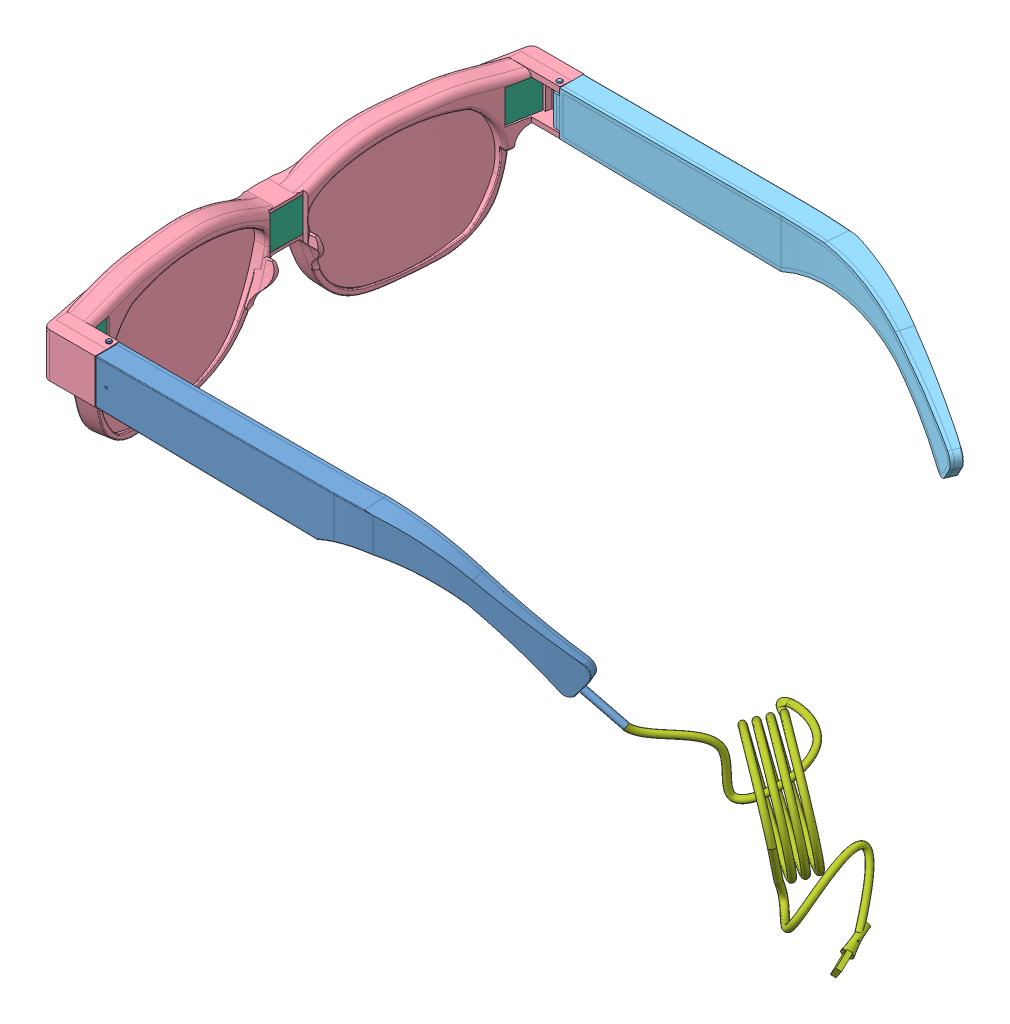
SolidWorks assembly Gafas WC 2023, configuration Default. Lengths in mm.
Overall size (222.66 106.19 146.27).
10 component instances, 7 part files, 27 mates.
Components (placement in the parent):
- Part1-1: Part1 [Default] at (-33.5143 33.5628 22.7781) size (139.98 37.93 22.05)
- Speaker chamber-1: Speaker chamber [Default] at (-37.5533 32.8602 20.2781) x (1 0 0) z (0 -1 0) size (14 4 6)
- PCB-4: PCB [Default] at (-77.7829 13.9335 20.2781) x (-1 0 0) z (0 1 0) size (45 3 10)
- frame-1: frame [Default] at (-140.5612 55.2655 184.5273) x (0 0 1) z (-1 0 0) size (143.47 53.42 27.49)
- Right Arm-1: Right Arm [Default] at (-38.6057 4.972 -63.5743) size (132.64 32.79 22.04)
- cmm-3: cmm [Default] at (-112.6806 14.0335 -108.5367) x (-0.178629 0 0.983916) z (-0.983916 0 -0.178629) size (10 10 7)
- cmm-4: cmm [Default] at (-119.3105 10.3315 -45.3241) x (0 1 0) z (-0.999885 0 -0.015171) size (10 10 7)
- cmm-6: cmm [Default] at (-112.6806 14.0335 17.7973) x (0 1 0) z (-0.983916 0 0.178629) size (10 10 7)
- Speaker chamber-3: Speaker chamber [Default] at (-38.8332 33.3633 -115.0175) x (1 0 0) z (0 -1 0) size (14 4 6)
- wire-1: wire [Default] at (9.152 -55.6539 -61.161) x (0.629187 0.526286 0.571967) z (0.535942 -0.826727 0.171142) size (40.55 44.6 63.29)
Mates (geometry in assembly coordinates):
- Coincident4: coincident anti-aligned: plane of Part1-1 through (-33.5143 33.5628 20.2781) normal (0 0 1); plane of Speaker chamber-1 through (-37.5533 32.8602 20.2781) normal (0 0 -1)
- Coincident5: coincident anti-aligned: line of Part1-1 through (-52.2245 9.2086 20.2781) axis (0 1 0); line of Speaker chamber-1 through (-52.2245 13.2086 20.2781) axis (0 -1 0)
- Coincident6: coincident: line of Part1-1 through (-48.1799 15.2086 20.2781) axis (1 0 0); plane of Speaker chamber-1 through (-38.2245 15.2086 24.2781) normal (0 1 0)
- Coincident13: coincident anti-aligned: plane of Part1-1 through (-33.5143 33.5628 20.2781) normal (0 0 1); plane of PCB-4 through (-77.7829 13.9335 20.2781) normal (0 0 -1)
- Coincident14: coincident: line of Part1-1 through (-100.2829 8.9335 20.2781) axis (0 1 0); plane of PCB-4 through (-100.2829 8.9335 21.2781) normal (-1 0 0)
- Coincident15: coincident: line of Part1-1 through (-100.2829 18.9335 20.2781) axis (1 0 0); plane of PCB-4 through (-100.2829 18.9335 21.2781) normal (0 1 0)
- Concentric1: concentric anti-aligned: cylinder of Part1-1 through (-105.0143 21.0335 20.7781) axis (0 -1 0) radius 0.75; cylinder of frame-1 through (-105.0143 -10.9665 20.7781) axis (0 1 0) radius 0.75
- Concentric2: concentric anti-aligned: cylinder of Part1-1 through (-105.0143 21.0335 20.7781) axis (0 -1 0) radius 0.75; cylinder of frame-1 through (-105.0143 -10.9665 20.7781) axis (0 1 0) radius 0.75
- Concentric3: concentric anti-aligned: cylinder of Part1-1 through (-105.0143 21.0335 20.7781) axis (0 -1 0) radius 0.75; cylinder of frame-1 through (-105.0143 -10.9665 20.7781) axis (0 1 0) radius 0.75
- Distance2: distance = 0.5 mm anti-aligned: plane of Part1-1 through (-103.5143 18.5335 22.2781) normal (0 1 0); plane of frame-1 through (207.2617 19.0335 -45.3697) normal (0 -1 0)
- LimitAngle1: limit planar angle = 0 rad anti-aligned: plane of Part1-1 through (-103.5143 33.5628 22.7781) normal (-1 0 0); plane of frame-1 through (-103.5143 22.0177 -25.1351) normal (1 0 0)
- Distance3: distance = 0.5 mm anti-aligned: plane of Right Arm-1 through (-106.5143 18.5335 -110.0175) normal (0 1 0); plane of frame-1 through (207.2617 19.0335 -45.3697) normal (0 -1 0)
- LimitAngle2: limit planar angle = 0 rad anti-aligned: plane of frame-1 through (-103.5143 22.0177 -65.6043) normal (1 0 0); plane of Right Arm-1 through (-103.5143 4.972 -113.5175) normal (-1 0 0)
- Tangent3: tangent: plane of assembly; face of frame-1; plane of cmm-3 through (-119.568 14.0335 -109.7871) normal (-0.983916 0 -0.178629)
- Coincident16: coincident anti-aligned: plane of frame-1 through (-117.0175 14.0335 -104.2423) normal (0.178629 0 -0.983916); plane of cmm-3 through (-120.4612 19.0335 -104.8675) normal (-0.178629 0 0.983916)
- Coincident17: coincident anti-aligned: plane of frame-1 through (207.2617 9.0335 -45.3697) normal (0 1 0); plane of cmm-3 through (-120.4612 9.0335 -104.8675) normal (0 -1 0)
- Coincident20: coincident anti-aligned: plane of frame-1 through (207.2617 5.3315 -45.3697) normal (0 1 0); plane of cmm-4 through (-126.2339 5.3315 -50.4297) normal (0 -1 0)
- Distance4: distance = 0 mm anti-aligned: plane of cmm-4 through (-126.2339 15.3315 -50.4297) normal (0.015171 0 -0.999885); plane of frame-1 through (-122.2804 10.3315 -50.3697) normal (-0.015171 0 0.999885)
- Tangent4: tangent: plane of assembly; face of frame-1; plane of cmm-6 through (-119.568 14.0335 19.0477) normal (-0.983916 0 0.178629)
- Coincident26: coincident anti-aligned: plane of frame-1 through (207.2617 19.0335 -45.3697) normal (0 -1 0); plane of cmm-6 through (-120.4612 19.0335 14.1281) normal (0 1 0)
- Coincident27: coincident anti-aligned: plane of frame-1 through (-117.0175 14.0335 13.5029) normal (0.178629 0 0.983916); plane of cmm-6 through (-120.4612 19.0335 14.1281) normal (-0.178629 0 -0.983916)
- Concentric4: concentric aligned: cylinder of frame-1 through (-105.0143 29.0335 -111.5175) axis (0 -1 0) radius 0.75; cylinder of Right Arm-1 through (-105.0143 21.0335 -111.5175) axis (0 -1 0) radius 0.75
- Coincident31: coincident anti-aligned: plane of Right Arm-1 through (-108.6057 24.972 -111.0175) normal (0 0 -1); plane of Speaker chamber-3 through (-38.8332 33.3633 -111.0175) normal (0 0 1)
- Coincident32: coincident: line of Right Arm-1 through (-49.4598 15.7117 -111.0175) axis (1 0 0); plane of Speaker chamber-3 through (-39.5044 15.7117 -111.0175) normal (0 1 0)
- Coincident33: coincident: line of Right Arm-1 through (-39.5044 15.7117 -111.0175) axis (0 -1 0); plane of Speaker chamber-3 through (-39.5044 11.7117 -111.0175) normal (1 0 0)
- Coincident34: coincident anti-aligned: plane of Part1-1 through (32.9187 -15.123 6.8635) normal (0.77579 -0.55894 -0.292809); plane of wire-1 through (33.0846 -14.9931 7.0552) normal (-0.77579 0.55894 0.292809)
- Coincident35: coincident anti-aligned: plane of Part1-1 through (32.9187 -15.123 6.8635) normal (0.77579 -0.55894 -0.292809); plane of wire-1 through (33.0846 -14.9931 7.0552) normal (-0.77579 0.55894 0.292809)
